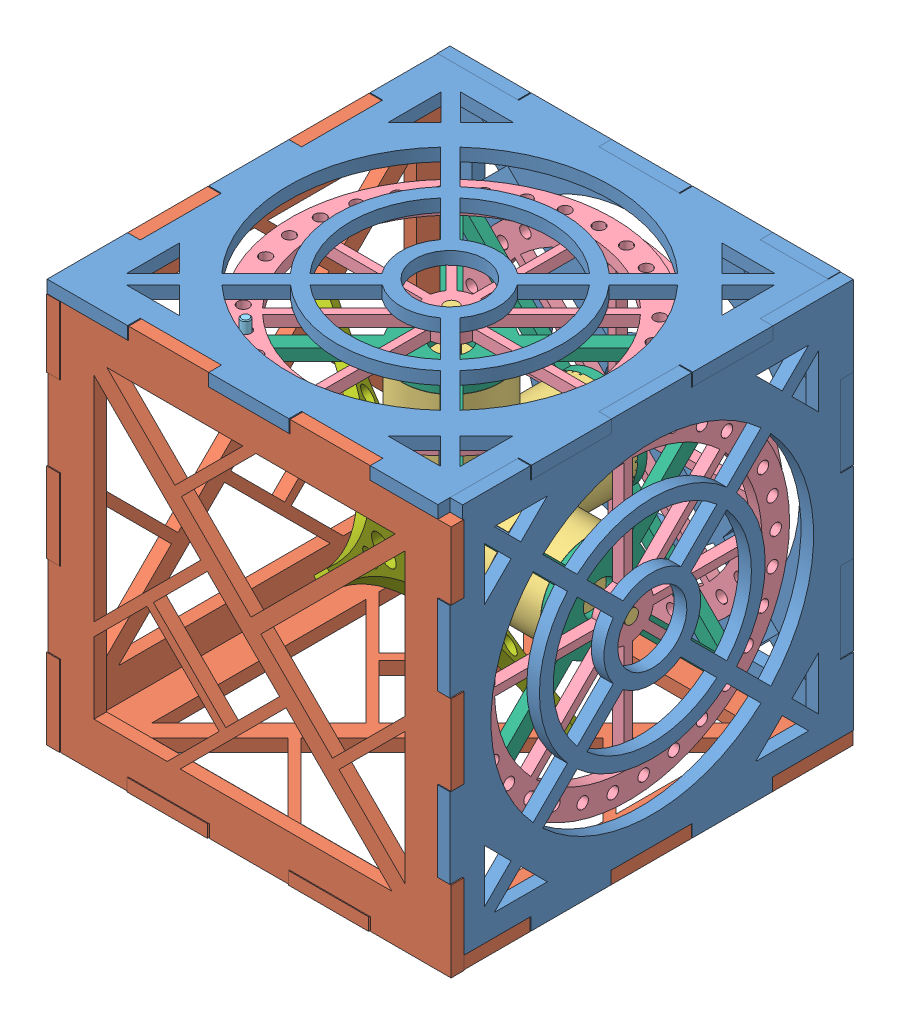
SolidWorks assembly Сборка, configuration По умолчанию. Lengths in mm.
Overall size (176.39 175 175.4).
17 component instances, 7 part files, 4 mates.
Components (placement in the parent):
- cтінка маховика-1: cтінка маховика [По умолчанию] at (-108.8174 -6.6044 112.9212) size (175 23 175)
- cтінка маховика-2: cтінка маховика [По умолчанию] at (-109.0174 -1.1044 -56.5788) x (1 0 0) z (0 1 0) size (175 23 175)
- cтінка маховика-3: cтінка маховика [По умолчанию] at (60.6826 -1.1044 -61.8788) x (0 0 1) z (0 1 0) size (175 23 175)
- стінка2-1: стінка2 [По умолчанию] at (-108.8174 -176.1048 113.1232) size (5.5 175 175)
- стінка2-2: стінка2 [По умолчанию] at (66.4621 -176.1048 112.9212) x (0 0 -1) z (1 0 0) size (5.5 175 175)
- стінка2-3: стінка2 [По умолчанию] at (66.1846 -176.1044 -61.6792) x (0 1 0) z (1 0 0) size (5.5 175 175)
- мотор-1: мотор [По умолчанию] at (-21.144 -61.7167 25.1249) size (42 50.5 42)
- маховик-1: маховик [По умолчанию] at (-21.144 -18.1751 25.1249) size (140 5 140)
- болт-1: болт [По умолчанию] at (-58.7623 -21.7992 76.902) size (8.98 13.5 8.86)
- мотор-3: мотор [По умолчанию] at (6.2037 -89.1446 24.8754) x (0 -1 0) z (0 0 1) size (42 50.5 42)
- маховик-3: маховик [По умолчанию] at (55.2755 -89.1446 24.8754) x (0 1 0) z (0 0 1) size (140 5 140)
- кріплення двигуна-4: кріплення двигуна [По умолчанию] at (-21.6368 -89.316 -39.2139) x (1 0 0) z (0 -1 0) size (122.36 5 122.36)
- мотор-4: мотор [По умолчанию] at (-21.6368 -89.316 -3.1252) x (1 0 0) z (0 1 0) size (42 50.5 42)
- маховик-4: маховик [По умолчанию] at (-21.6368 -89.316 -50.0337) x (1 0 0) z (0 -1 0) size (140 5 140)
- кріплення двигуна-5: кріплення двигуна [По умолчанию] at (-21.144 -29.6149 25.1249) size (122.36 5 122.36)
- кріплення двигуна-6: кріплення двигуна [По умолчанию] at (38.2721 -89.1446 24.8754) x (0 -1 0) z (0 0 1) size (122.36 5 122.36)
- полка-5: полка [По умолчанию] at (9.4192 -57.0302 115.4241) x (0.40668 -0.823552 -0.395441) z (0.71229 0.014791 0.70173) size (141.15 5 163.04)
Mates (geometry in assembly coordinates):
- Совпадение48: coincident aligned: line of cтінка маховика-1 through (-38.9174 -1.1044 -56.5788) axis (1 0 0); line of cтінка маховика-2 through (-38.9174 -1.1044 -56.5788) axis (1 0 0)
- Совпадение49: coincident aligned: line of cтінка маховика-1 through (-38.9174 -1.1044 -62.0788) axis (0 0 1); line of cтінка маховика-2 through (-38.9174 -1.1044 -62.0788) axis (0 0 1)
- Совпадение50: coincident anti-aligned: line of cтінка маховика-1 through (60.6826 -1.1044 43.0212) axis (0 0 -1); line of cтінка маховика-3 through (60.6826 -1.1044 8.2212) axis (0 0 1)
- Параллельность16: parallel aligned: line of cтінка маховика-1 through (66.1826 -1.1044 43.0212) axis (-1 0 0); line of cтінка маховика-3 through (66.1826 -1.1044 43.0212) axis (-1 0 0)
